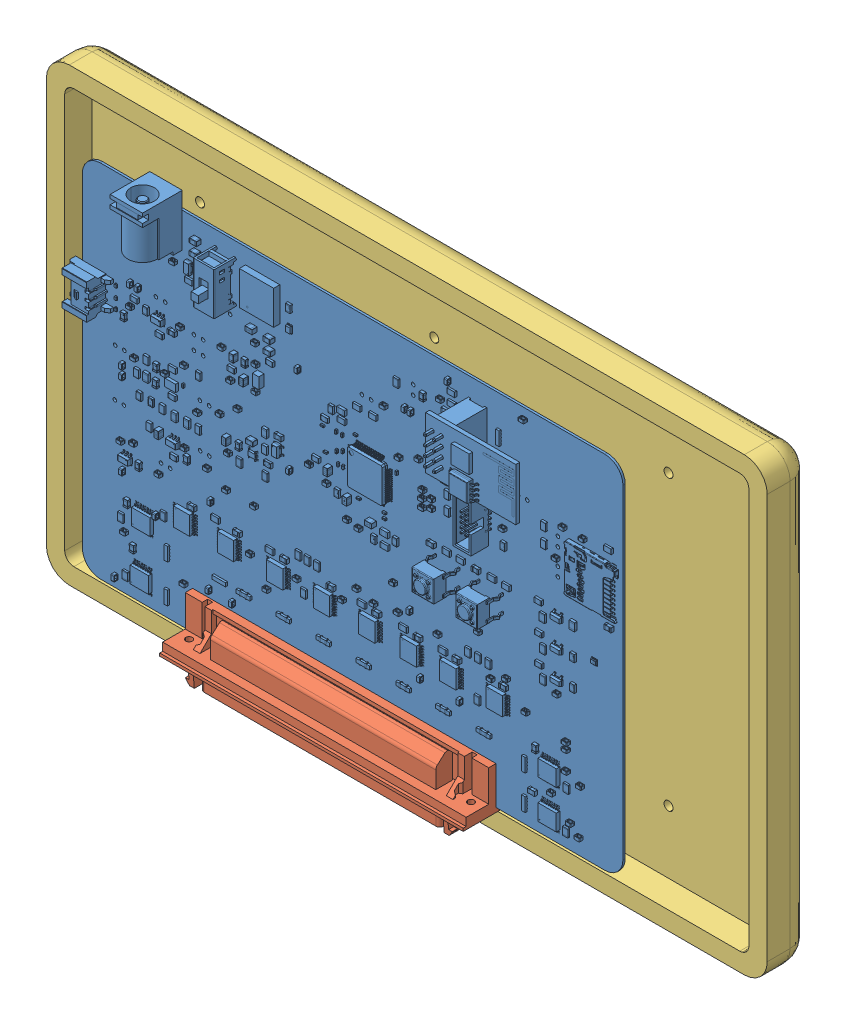
SolidWorks assembly PCB_CONN_ASSEMBLY, configuration Default. Lengths in mm.
Overall size (200 125.6 41.03).
3 component instances, 3 part files, 6 mates.
Components (placement in the parent):
- PCB-part-1: PCB-part [Default] at (-173.4358 35.6567 273.6027) size (151.91 104.79 21.14)
- 1-787082-8-part-1: 1-787082-8-part [Default] at (-75.0697 54.6286 277.5651) x (1 0 0) z (0 -1 0) size (84.2 13.31 16.87)
- Enclosure-1: Enclosure [Default] at (-72.7648 102.5104 245.869) x (1 0 0) z (0 -1 0) size (200 12.7 125)
Mates (geometry in assembly coordinates):
- Coincident1: coincident anti-aligned: plane of PCB-part-1 through (-147.7648 65.8227 273.6027) normal (0 0 1); plane of 1-787082-8-part-1 through (-109.2327 63.0614 273.6027) normal (0 0 -1)
- Coincident4: coincident anti-aligned: plane of PCB-part-1 through (-147.7648 65.8227 273.6027) normal (0 0 1); plane of 1-787082-8-part-1 through (-109.2327 63.0614 273.6027) normal (0 0 -1)
- Concentric8: concentric aligned: cylinder of PCB-part-1 through (-104.9147 64.3568 272.979) axis (0 0 -1) radius 0.4318
- Coincident7: coincident aligned: line of 1-787082-8-part-1 through (-104.7623 64.56 270.6817) axis (0 -1 0)
- Parallel2: parallel anti-aligned: plane of PCB-part-1 through (-147.7648 65.8227 272.979) normal (0 0 -1); plane of Enclosure-1 through (-72.7648 102.5104 250.949) normal (0 0 1)
- Width2: width anti-aligned: plane of Enclosure-1 through (-167.6848 159.9304 250.949) normal (1 0 0); plane of Enclosure-1 through (22.1552 159.9304 250.949) normal (-1 0 0); plane of PCB-part-1 through (-147.7648 155.8227 272.979) normal (-1 0 0); plane of PCB-part-1 through (2.2352 65.8227 272.979) normal (1 0 0)
